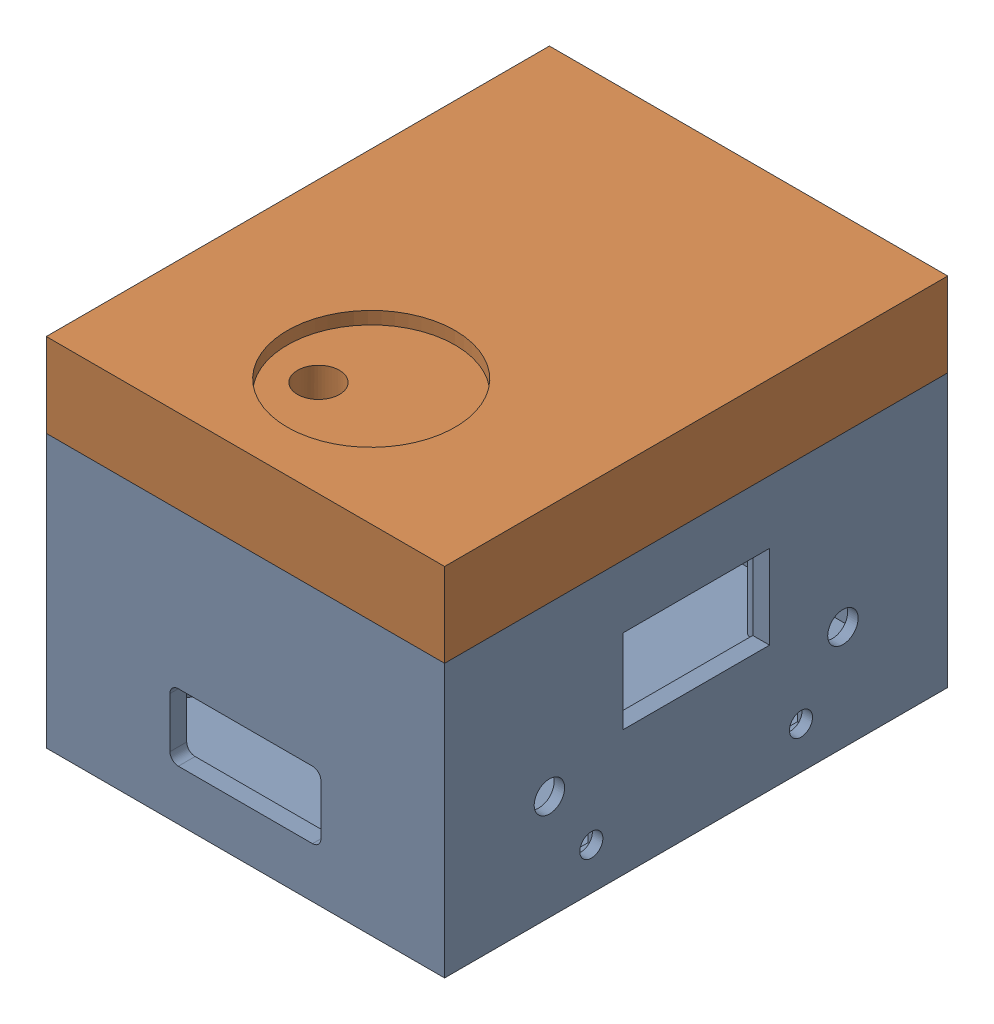
SolidWorks assembly Assem1, configuration Default. Lengths in mm.
Overall size (95 85 120).
2 component instances, 2 part files, 4 mates.
Components (placement in the parent):
- housing_base-1: housing_base [Default] at (22.0262 -34.7083 73.1243) size (95 65 120)
- housing_lid-1: housing_lid [Default] at (22.0262 30.2917 73.1243) size (95 35 120)
Mates (geometry in assembly coordinates):
- Coincident3: coincident: plane of housing_base-1 through (-25.4738 -29.7083 133.1243) normal (0 0 1); plane of housing_lid-1 through (-25.4738 50.2917 133.1243) normal (0 0 1)
- Coincident4: coincident: plane of housing_base-1 through (22.0262 30.2917 73.1243) normal (0 1 0); plane of housing_lid-1 through (22.0262 30.2917 73.1243) normal (0 -1 0)
- Coincident5: coincident: plane of housing_base-1 through (22.0262 30.2917 73.1243) normal (0 1 0); plane of housing_lid-1 through (22.0262 30.2917 73.1243) normal (0 -1 0)
- Coincident6: coincident aligned: plane of housing_base-1 through (69.5262 -29.7083 133.1243) normal (1 0 0); plane of housing_lid-1 through (69.5262 50.2917 133.1243) normal (1 0 0)
